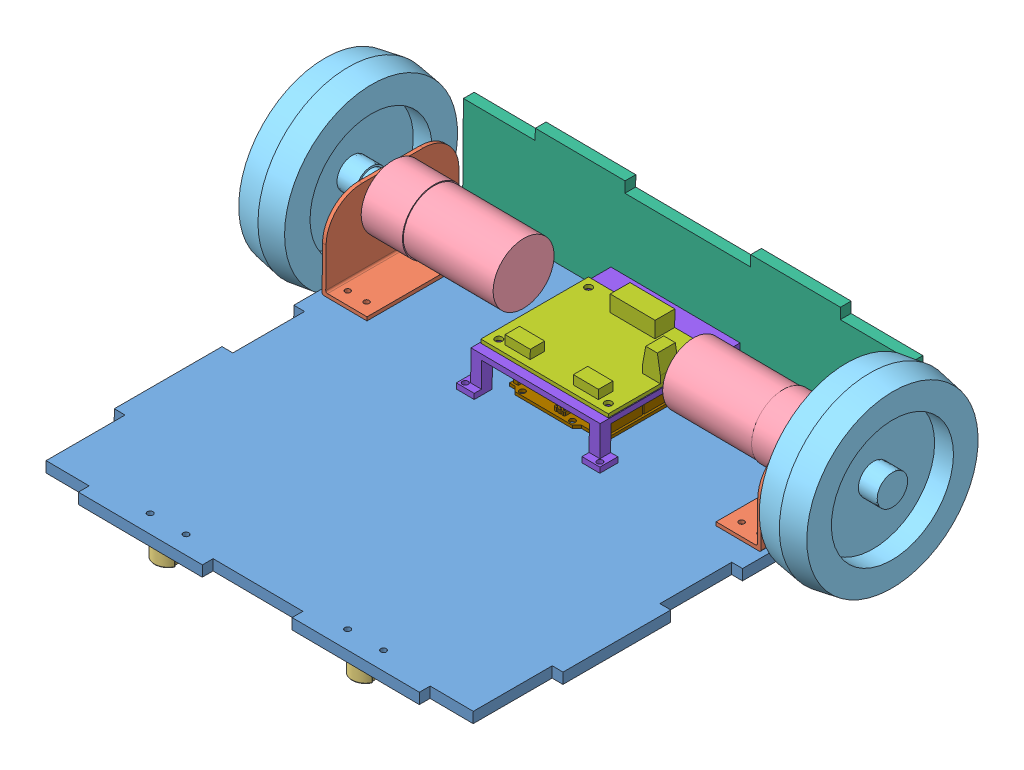
SolidWorks assembly BaseWheels, configuration Default. Lengths in mm.
Overall size (317.35 110.38 255.08).
13 component instances, 9 part files, 31 mates.
Components (placement in the parent):
- Base-1: Base [Default] at (88.9816 -302.6657 168.6836) x (0.999966 -0.008236 0.000093) z (-0.008236 -0.999966 0.000399) size (250 250 6)
- Motor Mount-1: Motor Mount [Default] at (-33.2608 -301.674 130.6722) x (0.999966 -0.008236 0.000093) z (-0.00009 0.0004 1) size (25 45 74)
- Motor Mount-2: Motor Mount [Default] at (211.2376 -303.7174 56.6951) x (-0.999966 0.008236 -0.000093) z (0.00009 -0.0004 -1) size (25 45 74)
- Ball Caster-1: Ball Caster [Default] at (143.8614 -316.1823 283.694) x (0.999966 -0.008236 0.000093) z (-0.00009 0.0004 1) size (25 13.46 15)
- Ball Caster-2: Ball Caster [Default] at (33.8651 -315.2763 283.6837) x (0.999966 -0.008236 0.000093) z (-0.00009 0.0004 1) size (25 13.46 15)
- Motor-1: Motor [Default] at (-31.0104 -271.7063 93.6604) x (0.000161 0.008235 -0.999966) z (0.999966 -0.008236 0.000093) size (35 35 85)
- Motor-2: Motor [Default] at (209.4814 -273.6872 93.6829) x (-0.000026 0.008237 0.999966) z (-0.999966 0.008236 -0.000093) size (35 35 85)
- Wheel-1: Wheel [Default] at (234.4805 -273.8931 93.6852) x (-0.000026 0.008237 0.999966) z (-0.999966 0.008236 -0.000093) size (100 100 36)
- Wheel-2: Wheel [Default] at (-56.0096 -271.5004 93.6581) x (-0.000785 -0.10656 -0.994306) z (0.999966 -0.008236 0.000093) size (100 100 36)
- Front-1: Front [Default] at (89.2112 -276.2166 43.6731) x (0.999966 -0.008236 0.000093) z (-0.00009 0.0004 1) size (250 65 6)
- MD25-1: MD25 [Default] at (53.6511 -282.3898 129.1723) x (0.999966 -0.008236 0.000093) z (-0.00009 0.0004 1) size (71 16 60)
- Table-1: Table [Default] at (88.9882 -302.6951 95.1836) x (-0.00009 0.0004 1) z (-0.999966 0.008236 -0.000093) size (86 20 80)
- Arduino UNO-1: Arduino UNO [Default] at (88.9702 -302.6975 88.8836) x (-0.00009 0.0004 1) z (-0.999966 0.008236 -0.000093) size (74.8 12.1 53.3)
Mates (geometry in assembly coordinates):
- Concentric1: concentric anti-aligned: circle of Motor Mount-2; circle of Base-1
- Concentric2: concentric anti-aligned: circle of Base-1; circle of Motor Mount-2
- Coincident1: coincident anti-aligned: plane of Base-1 through (88.9816 -302.6657 168.6836) normal (0.008236 0.999966 -0.000399); plane of Motor Mount-2 through (211.2376 -303.7174 56.6951) normal (-0.008236 -0.999966 0.000399)
- Concentric3: concentric aligned: circle of Base-1; circle of Motor Mount-1
- Coincident2: coincident anti-aligned: plane of Base-1 through (88.9816 -302.6657 168.6836) normal (0.008236 0.999966 -0.000399); plane of Motor Mount-1 through (-33.2608 -301.674 130.6722) normal (-0.008236 -0.999966 0.000399)
- Concentric6: concentric aligned: circle of Base-1; circle of Ball Caster-1
- Coincident3: coincident anti-aligned: plane of Base-1 through (88.9322 -308.6655 168.686) normal (-0.008236 -0.999966 0.000399); plane of Ball Caster-1 through (143.92 -309.0725 283.6912) normal (0.008236 0.999966 -0.000399)
- Concentric7: concentric aligned: circle of Base-1; circle of Ball Caster-2
- Coincident4: coincident anti-aligned: plane of Base-1 through (88.9322 -308.6655 168.686) normal (-0.008236 -0.999966 0.000399); plane of Ball Caster-2 through (33.9237 -308.1665 283.6809) normal (0.008236 0.999966 -0.000399)
- Coincident5: coincident anti-aligned: plane of Motor Mount-1 through (-30.8902 -256.692 130.6544) normal (0.999966 -0.008236 0.000093); plane of Motor-1 through (-31.0104 -271.7063 93.6604) normal (-0.999966 0.008236 -0.000093)
- Concentric8: concentric anti-aligned: cylinder of Motor Mount-1 through (-16.8688 -271.8228 93.6617) axis (-0.999966 0.008236 -0.000093) radius 5; cylinder of Motor-1 through (-33.0104 -271.6898 93.6602) axis (0.999966 -0.008236 0.000093) radius 5
- Coincident6: coincident anti-aligned: plane of Motor Mount-2 through (209.6083 -258.7025 56.6769) normal (-0.999966 0.008236 -0.000093); plane of Motor-2 through (209.4814 -273.6872 93.6829) normal (0.999966 -0.008236 0.000093)
- Concentric9: concentric anti-aligned: cylinder of Motor Mount-2 through (195.3397 -273.5707 93.6816) axis (0.999966 -0.008236 0.000093) radius 5; cylinder of Motor-2 through (211.4813 -273.7036 93.6831) axis (-0.999966 0.008236 -0.000093) radius 5
- Concentric10: concentric anti-aligned: cylinder of Motor-2 through (221.481 -273.786 93.684) axis (-0.999966 0.008236 -0.000093) radius 2.5; cylinder of Wheel-1 through (211.4813 -273.7036 93.6831) axis (0.999966 -0.008236 0.000093) radius 2.5
- Coincident7: coincident anti-aligned: plane of Motor-2 through (211.4813 -273.7036 93.6831) normal (0.999966 -0.008236 0.000093); plane of Wheel-1 through (211.4813 -273.7036 93.6831) normal (-0.999966 0.008236 -0.000093)
- Concentric12: concentric anti-aligned: cylinder of Motor-1 through (-43.01 -271.6075 93.6593) axis (0.999966 -0.008236 0.000093) radius 2.5; cylinder of Wheel-2 through (-33.0104 -271.6898 93.6602) axis (-0.999966 0.008236 -0.000093) radius 2.5
- Coincident8: coincident anti-aligned: plane of Motor-1 through (-33.0104 -271.6898 93.6602) normal (-0.999966 0.008236 -0.000093); plane of Wheel-2 through (-33.0104 -271.6898 93.6602) normal (0.999966 -0.008236 0.000093)
- Concentric13: concentric aligned: circle of Base-1; circle of Motor Mount-1
- Concentric14: concentric anti-aligned: circle of Base-1; circle of Ball Caster-1
- Concentric15: concentric anti-aligned: circle of Base-1; circle of Ball Caster-2
- Coincident9: coincident anti-aligned: line of Base-1 through (173.99 -303.4158 43.6916) axis (-0.00009 0.0004 1); line of Front-1 through (173.9895 -303.4134 49.6916) axis (0.00009 -0.0004 -1)
- Coincident10: coincident anti-aligned: line of Base-1 through (3.9958 -302.0156 43.6757) axis (-0.00009 0.0004 1); line of Front-1 through (3.9952 -302.0132 49.6757) axis (0.00009 -0.0004 -1)
- Coincident11: coincident anti-aligned: plane of Base-1 through (89.4726 -244.4058 49.6604) normal (0.00009 -0.0004 -1); plane of Front-1 through (89.2106 -276.2142 49.6731) normal (-0.00009 0.0004 1)
- Coincident13: coincident anti-aligned: plane of Base-1 through (88.9816 -302.6657 168.6836) normal (0.008236 0.999966 -0.000399); plane of Table-1 through (88.9882 -302.6951 95.1836) normal (-0.008236 -0.999966 0.000399)
- Coincident14: coincident anti-aligned: circle of Base-1; circle of Table-1
- Coincident15: coincident anti-aligned: circle of Base-1; circle of Table-1
- Coincident18: coincident anti-aligned: plane of MD25-1 through (53.6511 -282.3898 129.1723) normal (-0.008236 -0.999966 0.000399); plane of Table-1 through (89.153 -282.6958 95.1756) normal (0.008236 0.999966 -0.000399)
- Concentric16: concentric anti-aligned: circle of MD25-1; circle of Table-1
- Concentric17: concentric anti-aligned: circle of MD25-1; circle of Table-1
- Coincident19: coincident anti-aligned: plane of Base-1 through (88.9816 -302.6657 168.6836) normal (0.008236 0.999966 -0.000399); plane of Arduino UNO-1 through (115.954 -302.9013 135.0837) normal (-0.008236 -0.999966 0.000399)
- Coincident20: coincident anti-aligned: plane of Front-1 through (89.2106 -276.2142 49.6731) normal (-0.00009 0.0004 1); plane of Arduino UNO-1 through (106.7228 -290.759 49.6805) normal (0.00009 -0.0004 -1)
